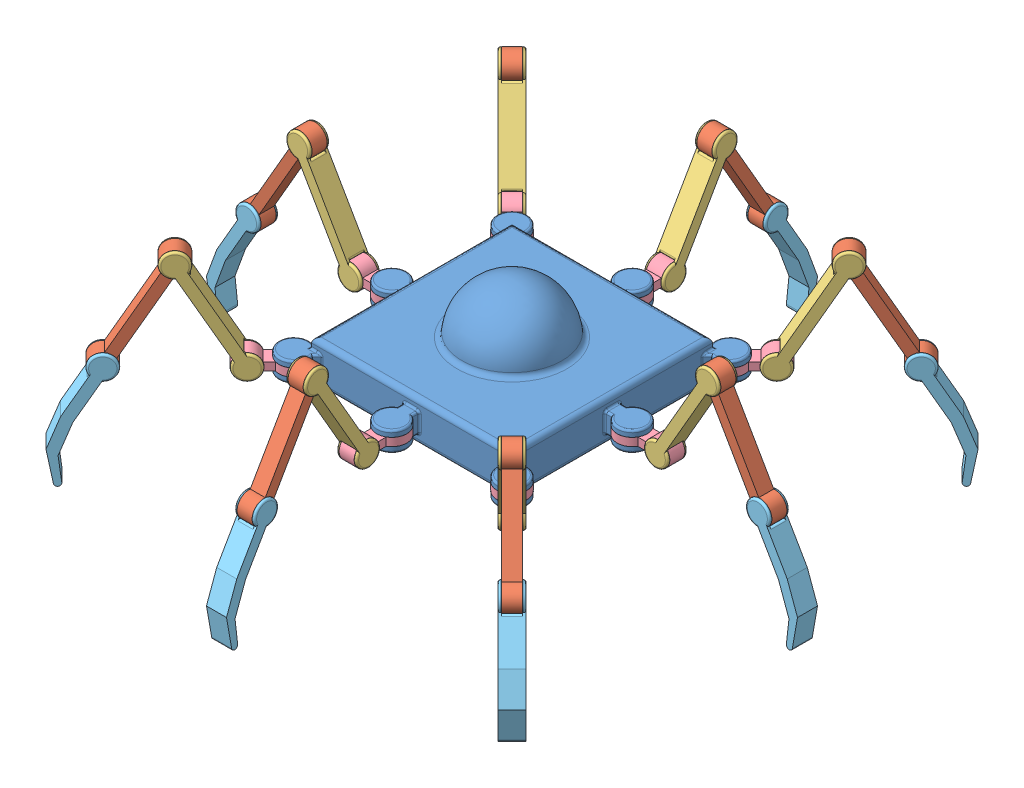
SolidWorks assembly SpiderBot_8Legs, configuration Default. Lengths in mm.
Overall size (634.89 207.45 634.89).
33 component instances, 5 part files, 146 mates.
Components (placement in the parent):
- spider_body-1: spider_body [Default] at (0 150 0) x (0 0 -1) z (0 -1 0) size (270 270 90)
- Link_C-24: Link_C [Default] at (-183.9152 176.5882 -194.5218) x (0.353553 0.866025 0.353553) z (-0.707107 0 0.707107) size (125.82 24 15)
- Link_B-24: Link_B [Default] at (-140.0258 176.5882 -154.1679) x (-0.707107 0 0.707107) z (-0.353553 0.866025 -0.353553) size (20.32 24 125.82)
- Link_A-24: Link_A [Default] at (-108.832 134 -108.832) x (-0.707107 0 -0.707107) z (0 -1 0) size (59.99 30 24)
- Link_D-24: Link_D [Default] at (-232.2874 88.4118 -218.1453) x (0.707107 0 -0.707107) z (0.353553 0.866025 0.353553) size (20.32 36.78 116.49)
- Link_C-26: Link_C [Default] at (-194.5218 176.5882 183.9152) x (0.353553 0.866025 -0.353553) z (0.707107 0 0.707107) size (125.82 24 15)
- Link_B-26: Link_B [Default] at (-154.1679 176.5882 140.0258) x (0.707107 0 0.707107) z (-0.353553 0.866025 0.353553) size (20.32 24 125.82)
- Link_A-26: Link_A [Default] at (-108.832 134 108.832) x (-0.707107 0 0.707107) z (0 -1 0) size (59.99 30 24)
- Link_D-26: Link_D [Default] at (-218.1453 88.4118 232.2874) x (-0.707107 0 -0.707107) z (0.353553 0.866025 -0.353553) size (20.32 36.78 116.49)
- Link_C-27: Link_C [Default] at (183.9152 176.5882 194.5218) x (-0.353553 0.866025 -0.353553) z (0.707107 0 -0.707107) size (125.82 24 15)
- Link_B-27: Link_B [Default] at (140.0258 176.5882 154.1679) x (0.707107 0 -0.707107) z (0.353553 0.866025 0.353553) size (20.32 24 125.82)
- Link_A-27: Link_A [Default] at (108.832 134 108.832) x (0.707107 0 0.707107) z (0 -1 0) size (59.99 30 24)
- Link_D-27: Link_D [Default] at (232.2874 88.4118 218.1453) x (-0.707107 0 0.707107) z (-0.353553 0.866025 -0.353553) size (20.32 36.78 116.49)
- Link_B-33: Link_B [Default] at (154.1679 176.5882 -140.0258) x (-0.707107 0 -0.707107) z (0.353553 0.866025 -0.353553) size (20.32 24 125.82)
- Link_D-31: Link_D [Default] at (218.1453 88.4118 -232.2874) x (0.707107 0 0.707107) z (-0.353553 0.866025 0.353553) size (20.32 36.78 116.49)
- Link_A-31: Link_A [Default] at (108.832 134 -108.832) x (0.707107 0 -0.707107) z (0 -1 0) size (59.99 30 24)
- Link_C-31: Link_C [Default] at (194.5218 176.5882 -183.9152) x (-0.353553 0.866025 0.353553) z (-0.707107 0 -0.707107) size (125.82 24 15)
- Link_D-34: Link_D [Default] at (-284.5923 88.4118 10) x (0 0 -1) z (0.5 0.866025 0) size (20.32 36.78 116.49)
- Link_A-34: Link_A [Default] at (-120 134 0) x (-1 0 0) z (0 -1 0) size (59.99 30 24)
- Link_B-36: Link_B [Default] at (-174.1146 176.5882 -10) x (0 0 1) z (-0.5 0.866025 0) size (20.32 24 125.82)
- Link_C-34: Link_C [Default] at (-233.6836 176.5882 -7.5) x (0.5 0.866025 0) z (0 0 1) size (125.82 24 15)
- Link_A-35: Link_A [Default] at (120 134 0) x (1 0 0) z (0 -1 0) size (59.99 30 24)
- Link_D-35: Link_D [Default] at (284.5923 88.4118 -10) x (0 0 1) z (-0.5 0.866025 0) size (20.32 36.78 116.49)
- Link_C-35: Link_C [Default] at (233.6836 176.5882 7.5) x (-0.5 0.866025 0) z (0 0 -1) size (125.82 24 15)
- Link_B-37: Link_B [Default] at (174.1146 176.5882 10) x (0 0 -1) z (0.5 0.866025 0) size (20.32 24 125.82)
- Link_A-36: Link_A [Default] at (0 134 120) x (0 0 1) z (0 -1 0) size (59.99 30 24)
- Link_D-36: Link_D [Default] at (10 88.4118 284.5923) x (-1 0 0) z (0 0.866025 -0.5) size (20.32 36.78 116.49)
- Link_C-36: Link_C [Default] at (-7.5 176.5882 233.6836) x (0 0.866025 -0.5) z (1 0 0) size (125.82 24 15)
- Link_B-38: Link_B [Default] at (-10 176.5882 174.1146) x (1 0 0) z (0 0.866025 0.5) size (20.32 24 125.82)
- Link_A-37: Link_A [Default] at (0 134 -120) x (0 0 -1) z (0 -1 0) size (59.99 30 24)
- Link_D-37: Link_D [Default] at (-10 88.4118 -284.5923) x (1 0 0) z (0 0.866025 0.5) size (20.32 36.78 116.49)
- Link_C-37: Link_C [Default] at (7.5 176.5882 -233.6836) x (0 0.866025 0.5) z (-1 0 0) size (125.82 24 15)
- Link_B-39: Link_B [Default] at (10 176.5882 -174.1146) x (-1 0 0) z (0 0.866025 -0.5) size (20.32 24 125.82)
Mates (geometry in assembly coordinates):
- Coincident4: coincident anti-aligned: plane of Link_B-2 through (235.0341 -365.5738 720.8033) normal (-1 0 0); plane of Link_C-2 through (235.0341 -453.7502 771.712) normal (1 0 0)
- Concentric4: concentric anti-aligned: cylinder of Link_B-2 through (220.0341 -365.5738 720.8033) axis (1 0 0) radius 4; cylinder of Link_C-2 through (235.0341 -365.5738 720.8033) axis (-1 0 0) radius 4
- Coincident5: coincident anti-aligned: plane of Link_C-2 through (235.0341 -453.7502 771.712) normal (1 0 0); plane of Link_D-2 through (235.0341 -453.7502 771.712) normal (-1 0 0)
- Concentric6: concentric aligned: cylinder of Link_C-2 through (235.0341 -453.7502 771.712) axis (-1 0 0) radius 4; cylinder of Link_D-2 through (235.0341 -453.7502 771.712) axis (-1 0 0) radius 4
- Coincident7: coincident anti-aligned: plane of Link_B-3 through (281.248 -759.0313 934.2797) normal (-1 0 0); plane of Link_C-3 through (281.248 -847.2078 985.1885) normal (1 0 0)
- Concentric7: concentric anti-aligned: cylinder of Link_B-3 through (266.248 -759.0313 934.2797) axis (1 0 0) radius 4; cylinder of Link_C-3 through (281.248 -759.0313 934.2797) axis (-1 0 0) radius 4
- Coincident8: coincident anti-aligned: plane of Link_C-3 through (281.248 -847.2078 985.1885) normal (1 0 0); plane of Link_D-3 through (281.248 -847.2078 985.1885) normal (-1 0 0)
- Concentric9: concentric aligned: cylinder of Link_C-3 through (281.248 -847.2078 985.1885) axis (-1 0 0) radius 4; cylinder of Link_D-3 through (281.248 -847.2078 985.1885) axis (-1 0 0) radius 4
- Coincident10: coincident anti-aligned: plane of Link_B-4 through (178.5336 -465.5708 822.703) normal (-1 0 0); plane of Link_C-4 through (178.5336 -553.7473 873.6117) normal (1 0 0)
- Concentric10: concentric anti-aligned: cylinder of Link_B-4 through (163.5336 -465.5708 822.703) axis (1 0 0) radius 4; cylinder of Link_C-4 through (178.5336 -465.5708 822.703) axis (-1 0 0) radius 4
- Coincident11: coincident anti-aligned: plane of Link_C-4 through (178.5336 -553.7473 873.6117) normal (1 0 0); plane of Link_D-4 through (178.5336 -553.7473 873.6117) normal (-1 0 0)
- Concentric12: concentric aligned: cylinder of Link_C-4 through (178.5336 -553.7473 873.6117) axis (-1 0 0) radius 4; cylinder of Link_D-4 through (178.5336 -553.7473 873.6117) axis (-1 0 0) radius 4
- Coincident13: coincident anti-aligned: plane of Link_B-5 through (262.376 -1013.0932 1106.1332) normal (-1 0 0); plane of Link_C-5 through (262.376 -1101.2696 1157.0419) normal (1 0 0)
- Concentric13: concentric anti-aligned: cylinder of Link_B-5 through (247.376 -1013.0932 1106.1332) axis (1 0 0) radius 4; cylinder of Link_C-5 through (262.376 -1013.0932 1106.1332) axis (-1 0 0) radius 4
- Coincident14: coincident anti-aligned: plane of Link_C-5 through (262.376 -1101.2696 1157.0419) normal (1 0 0); plane of Link_D-5 through (262.376 -1101.2696 1157.0419) normal (-1 0 0)
- Concentric15: concentric aligned: cylinder of Link_C-5 through (262.376 -1101.2696 1157.0419) axis (-1 0 0) radius 4; cylinder of Link_D-5 through (262.376 -1101.2696 1157.0419) axis (-1 0 0) radius 4
- Coincident16: coincident anti-aligned: plane of Link_B-6 through (534.9738 -1642.7072 1309.0583) normal (-1 0 0); plane of Link_C-6 through (534.9738 -1730.8837 1359.9671) normal (1 0 0)
- Concentric16: concentric anti-aligned: cylinder of Link_B-6 through (519.9738 -1642.7072 1309.0583) axis (1 0 0) radius 4; cylinder of Link_C-6 through (534.9738 -1642.7072 1309.0583) axis (-1 0 0) radius 4
- Coincident17: coincident anti-aligned: plane of Link_C-6 through (534.9738 -1730.8837 1359.9671) normal (1 0 0); plane of Link_D-6 through (534.9738 -1730.8837 1359.9671) normal (-1 0 0)
- Concentric18: concentric aligned: cylinder of Link_C-6 through (534.9738 -1730.8837 1359.9671) axis (-1 0 0) radius 4; cylinder of Link_D-6 through (534.9738 -1730.8837 1359.9671) axis (-1 0 0) radius 4
- Coincident19: coincident anti-aligned: plane of Link_B-7 through (-306.3909 -269.9837 1039.0888) normal (-1 0 0); plane of Link_C-7 through (-306.3909 -358.1602 1089.9975) normal (1 0 0)
- Concentric19: concentric anti-aligned: cylinder of Link_B-7 through (-321.3909 -269.9837 1039.0888) axis (1 0 0) radius 4; cylinder of Link_C-7 through (-306.3909 -269.9837 1039.0888) axis (-1 0 0) radius 4
- Coincident20: coincident anti-aligned: plane of Link_C-7 through (-306.3909 -358.1602 1089.9975) normal (1 0 0); plane of Link_D-7 through (-306.3909 -358.1602 1089.9975) normal (-1 0 0)
- Concentric21: concentric aligned: cylinder of Link_C-7 through (-306.3909 -358.1602 1089.9975) axis (-1 0 0) radius 4; cylinder of Link_D-7 through (-306.3909 -358.1602 1089.9975) axis (-1 0 0) radius 4
- Coincident22: coincident anti-aligned: plane of Link_B-8 through (-311.8852 -488.0983 1179.1514) normal (-1 0 0); plane of Link_C-8 through (-311.8852 -576.2747 1230.0601) normal (1 0 0)
- Concentric22: concentric anti-aligned: cylinder of Link_B-8 through (-326.8852 -488.0983 1179.1514) axis (1 0 0) radius 4; cylinder of Link_C-8 through (-311.8852 -488.0983 1179.1514) axis (-1 0 0) radius 4
- Coincident23: coincident anti-aligned: plane of Link_C-8 through (-311.8852 -576.2747 1230.0601) normal (1 0 0); plane of Link_D-8 through (-311.8852 -576.2747 1230.0601) normal (-1 0 0)
- Concentric24: concentric aligned: cylinder of Link_C-8 through (-311.8852 -576.2747 1230.0601) axis (-1 0 0) radius 4; cylinder of Link_D-8 through (-311.8852 -576.2747 1230.0601) axis (-1 0 0) radius 4
- Coincident25: coincident anti-aligned: plane of Link_B-9 through (-611.4857 -390.9688 1327.6493) normal (-1 0 0); plane of Link_C-9 through (-611.4857 -479.1453 1378.558) normal (1 0 0)
- Concentric25: concentric anti-aligned: cylinder of Link_B-9 through (-626.4857 -390.9688 1327.6493) axis (1 0 0) radius 4; cylinder of Link_C-9 through (-611.4857 -390.9688 1327.6493) axis (-1 0 0) radius 4
- Coincident26: coincident anti-aligned: plane of Link_C-9 through (-611.4857 -479.1453 1378.558) normal (1 0 0); plane of Link_D-9 through (-611.4857 -479.1453 1378.558) normal (-1 0 0)
- Concentric27: concentric aligned: cylinder of Link_C-9 through (-611.4857 -479.1453 1378.558) axis (-1 0 0) radius 4; cylinder of Link_D-9 through (-611.4857 -479.1453 1378.558) axis (-1 0 0) radius 4
- Coincident28: coincident anti-aligned: plane of Link_B-10 through (-139.42 -657.5126 1164.5577) normal (-1 0 0); plane of Link_C-10 through (-139.42 -745.689 1215.4664) normal (1 0 0)
- Concentric28: concentric anti-aligned: cylinder of Link_B-10 through (-154.42 -657.5126 1164.5577) axis (1 0 0) radius 4; cylinder of Link_C-10 through (-139.42 -657.5126 1164.5577) axis (-1 0 0) radius 4
- Coincident29: coincident anti-aligned: plane of Link_C-10 through (-139.42 -745.689 1215.4664) normal (1 0 0); plane of Link_D-10 through (-139.42 -745.689 1215.4664) normal (-1 0 0)
- Concentric30: concentric aligned: cylinder of Link_C-10 through (-139.42 -745.689 1215.4664) axis (-1 0 0) radius 4; cylinder of Link_D-10 through (-139.42 -745.689 1215.4664) axis (-1 0 0) radius 4
- Coincident31: coincident anti-aligned: plane of Link_B-11 through (-139.42 -657.5126 1164.5577) normal (-1 0 0); plane of Link_C-11 through (-139.42 -745.689 1215.4664) normal (1 0 0)
- Concentric31: concentric anti-aligned: cylinder of Link_B-11 through (-154.42 -657.5126 1164.5577) axis (1 0 0) radius 4; cylinder of Link_C-11 through (-139.42 -657.5126 1164.5577) axis (-1 0 0) radius 4
- Coincident32: coincident anti-aligned: plane of Link_C-11 through (-139.42 -745.689 1215.4664) normal (1 0 0); plane of Link_D-11 through (-139.42 -745.689 1215.4664) normal (-1 0 0)
- Concentric33: concentric aligned: cylinder of Link_C-11 through (-139.42 -745.689 1215.4664) axis (-1 0 0) radius 4; cylinder of Link_D-11 through (-139.42 -745.689 1215.4664) axis (-1 0 0) radius 4
- Coincident34: coincident anti-aligned: plane of Link_B-12 through (-94.7509 -804.43 1225.1322) normal (-1 0 0); plane of Link_C-12 through (-94.7509 -892.6065 1276.0409) normal (1 0 0)
- Concentric34: concentric anti-aligned: cylinder of Link_B-12 through (-109.7509 -804.43 1225.1322) axis (1 0 0) radius 4; cylinder of Link_C-12 through (-94.7509 -804.43 1225.1322) axis (-1 0 0) radius 4
- Coincident35: coincident anti-aligned: plane of Link_C-12 through (-94.7509 -892.6065 1276.0409) normal (1 0 0); plane of Link_D-12 through (-94.7509 -892.6065 1276.0409) normal (-1 0 0)
- Concentric36: concentric aligned: cylinder of Link_C-12 through (-94.7509 -892.6065 1276.0409) axis (-1 0 0) radius 4; cylinder of Link_D-12 through (-94.7509 -892.6065 1276.0409) axis (-1 0 0) radius 4
- Concentric78: concentric anti-aligned: cylinder of Link_C-24 through (-173.461 218.1765 -162.8544) axis (0.707107 0 -0.707107) radius 4; cylinder of Link_B-24 through (-162.8544 218.1765 -173.461) axis (-0.707107 0 0.707107) radius 4
- Concentric79: concentric anti-aligned: cylinder of Link_B-24 through (-126.8565 130 -137.4631) axis (-0.707107 0 0.707107) radius 4; cylinder of Link_A-24 through (-142.7664 130 -121.5532) axis (0.707107 0 -0.707107) radius 5
- Coincident86: coincident anti-aligned: plane of Link_B-24 through (-137.4631 130 -126.8565) normal (0.707107 0 -0.707107); plane of Link_A-24 through (-123.3209 126 -112.7143) normal (-0.707107 0 0.707107)
- Coincident87: coincident anti-aligned: plane of Link_C-24 through (-198.8522 130 -209.4588) normal (0.707107 0 -0.707107); plane of Link_B-24 through (-162.8544 218.1765 -173.461) normal (-0.707107 0 0.707107)
- Coincident88: coincident anti-aligned: plane of Link_C-24 through (-209.4588 130 -198.8522) normal (-0.707107 0 0.707107); plane of Link_B-24 through (-173.461 218.1765 -162.8544) normal (0.707107 0 -0.707107)
- Coincident89: coincident anti-aligned: plane of Link_C-24 through (-198.8522 130 -209.4588) normal (0.707107 0 -0.707107); plane of Link_D-24 through (-198.8522 130 -209.4588) normal (-0.707107 0 0.707107)
- Concentric80: concentric aligned: cylinder of Link_C-24 through (-209.4588 130 -198.8522) axis (0.707107 0 -0.707107) radius 4; cylinder of Link_D-24 through (-209.4588 130 -198.8522) axis (0.707107 0 -0.707107) radius 4
- Coincident90: coincident anti-aligned: plane of Link_B-24 through (-126.8565 130 -137.4631) normal (-0.707107 0 0.707107); plane of Link_A-24 through (-112.7143 126 -123.3209) normal (0.707107 0 -0.707107)
- Coincident91: coincident anti-aligned: plane of Link_C-24 through (-209.4588 130 -198.8522) normal (-0.707107 0 0.707107); plane of Link_D-24 through (-209.4588 130 -198.8522) normal (0.707107 0 -0.707107)
- Concentric84: concentric anti-aligned: cylinder of Link_C-26 through (-162.8544 218.1765 173.461) axis (-0.707107 0 -0.707107) radius 4; cylinder of Link_B-26 through (-173.461 218.1765 162.8544) axis (0.707107 0 0.707107) radius 4
- Concentric85: concentric anti-aligned: cylinder of Link_B-26 through (-137.4631 130 126.8565) axis (0.707107 0 0.707107) radius 4; cylinder of Link_A-26 through (-121.5532 130 142.7664) axis (-0.707107 0 -0.707107) radius 5
- Coincident98: coincident anti-aligned: plane of Link_B-26 through (-126.8565 130 137.4631) normal (-0.707107 0 -0.707107); plane of Link_A-26 through (-112.7143 126 123.3209) normal (0.707107 0 0.707107)
- Coincident99: coincident anti-aligned: plane of Link_C-26 through (-209.4588 130 198.8522) normal (-0.707107 0 -0.707107); plane of Link_B-26 through (-173.461 218.1765 162.8544) normal (0.707107 0 0.707107)
- Coincident100: coincident anti-aligned: plane of Link_C-26 through (-198.8522 130 209.4588) normal (0.707107 0 0.707107); plane of Link_B-26 through (-162.8544 218.1765 173.461) normal (-0.707107 0 -0.707107)
- Coincident101: coincident anti-aligned: plane of Link_C-26 through (-209.4588 130 198.8522) normal (-0.707107 0 -0.707107); plane of Link_D-26 through (-209.4588 130 198.8522) normal (0.707107 0 0.707107)
- Concentric86: concentric aligned: cylinder of Link_C-26 through (-198.8522 130 209.4588) axis (-0.707107 0 -0.707107) radius 4; cylinder of Link_D-26 through (-198.8522 130 209.4588) axis (-0.707107 0 -0.707107) radius 4
- Coincident102: coincident anti-aligned: plane of Link_B-26 through (-137.4631 130 126.8565) normal (0.707107 0 0.707107); plane of Link_A-26 through (-123.3209 126 112.7143) normal (-0.707107 0 -0.707107)
- Coincident103: coincident anti-aligned: plane of Link_C-26 through (-198.8522 130 209.4588) normal (0.707107 0 0.707107); plane of Link_D-26 through (-198.8522 130 209.4588) normal (-0.707107 0 -0.707107)
- Concentric87: concentric anti-aligned: cylinder of Link_C-27 through (173.461 218.1765 162.8544) axis (-0.707107 0 0.707107) radius 4; cylinder of Link_B-27 through (162.8544 218.1765 173.461) axis (0.707107 0 -0.707107) radius 4
- Concentric88: concentric anti-aligned: cylinder of Link_B-27 through (126.8565 130 137.4631) axis (0.707107 0 -0.707107) radius 4; cylinder of Link_A-27 through (142.7664 130 121.5532) axis (-0.707107 0 0.707107) radius 5
- Coincident104: coincident anti-aligned: plane of Link_B-27 through (137.4631 130 126.8565) normal (-0.707107 0 0.707107); plane of Link_A-27 through (123.3209 126 112.7143) normal (0.707107 0 -0.707107)
- Coincident105: coincident anti-aligned: plane of Link_C-27 through (198.8522 130 209.4588) normal (-0.707107 0 0.707107); plane of Link_B-27 through (162.8544 218.1765 173.461) normal (0.707107 0 -0.707107)
- Coincident106: coincident anti-aligned: plane of Link_C-27 through (209.4588 130 198.8522) normal (0.707107 0 -0.707107); plane of Link_B-27 through (173.461 218.1765 162.8544) normal (-0.707107 0 0.707107)
- Coincident107: coincident anti-aligned: plane of Link_C-27 through (198.8522 130 209.4588) normal (-0.707107 0 0.707107); plane of Link_D-27 through (198.8522 130 209.4588) normal (0.707107 0 -0.707107)
- Concentric89: concentric aligned: cylinder of Link_C-27 through (209.4588 130 198.8522) axis (-0.707107 0 0.707107) radius 4; cylinder of Link_D-27 through (209.4588 130 198.8522) axis (-0.707107 0 0.707107) radius 4
- Coincident108: coincident anti-aligned: plane of Link_B-27 through (126.8565 130 137.4631) normal (0.707107 0 -0.707107); plane of Link_A-27 through (112.7143 126 123.3209) normal (-0.707107 0 0.707107)
- Coincident109: coincident anti-aligned: plane of Link_C-27 through (209.4588 130 198.8522) normal (0.707107 0 -0.707107); plane of Link_D-27 through (209.4588 130 198.8522) normal (-0.707107 0 0.707107)
- Coincident124: coincident anti-aligned: plane of spider_body-1 through (108.832 134 108.832) normal (0 -1 0); plane of Link_A-27 through (108.832 134 108.832) normal (0 1 0)
- Coincident125: coincident anti-aligned: plane of spider_body-1 through (108.832 126 108.832) normal (0 1 0); plane of Link_A-27 through (108.832 126 108.832) normal (0 -1 0)
- Concentric97: concentric anti-aligned: cylinder of spider_body-1 through (108.832 134 108.832) axis (0 -1 0) radius 10; cylinder of Link_A-27 through (108.832 126 108.832) axis (0 1 0) radius 10
- Coincident126: coincident anti-aligned: plane of spider_body-1 through (-108.832 134 108.832) normal (0 -1 0); plane of Link_A-26 through (-108.832 134 108.832) normal (0 1 0)
- Coincident127: coincident anti-aligned: plane of spider_body-1 through (-108.832 126 108.832) normal (0 1 0); plane of Link_A-26 through (-108.832 126 108.832) normal (0 -1 0)
- Concentric98: concentric anti-aligned: cylinder of spider_body-1 through (-108.832 134 108.832) axis (0 -1 0) radius 10; cylinder of Link_A-26 through (-108.832 126 108.832) axis (0 1 0) radius 10
- Coincident138: coincident anti-aligned: plane of Link_B-33 through (162.8544 218.1765 -173.461) normal (0.707107 0 0.707107); plane of Link_C-31 through (198.8522 130 -209.4588) normal (-0.707107 0 -0.707107)
- Coincident139: coincident anti-aligned: plane of Link_D-31 through (209.4588 130 -198.8522) normal (-0.707107 0 -0.707107); plane of Link_C-31 through (209.4588 130 -198.8522) normal (0.707107 0 0.707107)
- Coincident140: coincident anti-aligned: plane of Link_D-31 through (198.8522 130 -209.4588) normal (0.707107 0 0.707107); plane of Link_C-31 through (198.8522 130 -209.4588) normal (-0.707107 0 -0.707107)
- Concentric104: concentric aligned: cylinder of Link_D-31 through (198.8522 130 -209.4588) axis (0.707107 0 0.707107) radius 4; cylinder of Link_C-31 through (198.8522 130 -209.4588) axis (0.707107 0 0.707107) radius 4
- Coincident141: coincident anti-aligned: plane of Link_B-33 through (137.4631 130 -126.8565) normal (-0.707107 0 -0.707107); plane of Link_A-31 through (123.3209 126 -112.7143) normal (0.707107 0 0.707107)
- Concentric105: concentric anti-aligned: cylinder of Link_B-33 through (173.461 218.1765 -162.8544) axis (-0.707107 0 -0.707107) radius 4; cylinder of Link_C-31 through (162.8544 218.1765 -173.461) axis (0.707107 0 0.707107) radius 4
- Concentric106: concentric anti-aligned: cylinder of Link_B-33 through (137.4631 130 -126.8565) axis (-0.707107 0 -0.707107) radius 4; cylinder of Link_A-31 through (121.5532 130 -142.7664) axis (0.707107 0 0.707107) radius 5
- Coincident142: coincident anti-aligned: plane of Link_B-33 through (126.8565 130 -137.4631) normal (0.707107 0 0.707107); plane of Link_A-31 through (112.7143 126 -123.3209) normal (-0.707107 0 -0.707107)
- Coincident143: coincident anti-aligned: plane of Link_B-33 through (173.461 218.1765 -162.8544) normal (-0.707107 0 -0.707107); plane of Link_C-31 through (209.4588 130 -198.8522) normal (0.707107 0 0.707107)
- Coincident146: coincident anti-aligned: plane of spider_body-1 through (108.832 134 -108.832) normal (0 -1 0); plane of Link_A-31 through (108.832 134 -108.832) normal (0 1 0)
- Coincident147: coincident anti-aligned: plane of spider_body-1 through (108.832 126 -108.832) normal (0 1 0); plane of Link_A-31 through (108.832 126 -108.832) normal (0 -1 0)
- Concentric108: concentric anti-aligned: cylinder of spider_body-1 through (108.832 134 -108.832) axis (0 -1 0) radius 10; cylinder of Link_A-31 through (108.832 126 -108.832) axis (0 1 0) radius 10
- Coincident148: coincident anti-aligned: plane of spider_body-1 through (-108.832 134 -108.832) normal (0 -1 0); plane of Link_A-24 through (-108.832 134 -108.832) normal (0 1 0)
- Coincident149: coincident anti-aligned: plane of spider_body-1 through (-108.832 126 -108.832) normal (0 1 0); plane of Link_A-24 through (-108.832 126 -108.832) normal (0 -1 0)
- Concentric109: concentric anti-aligned: cylinder of spider_body-1 through (-108.832 134 -108.832) axis (0 -1 0) radius 10; cylinder of Link_A-24 through (-108.832 126 -108.832) axis (0 1 0) radius 10
- Concentric111: concentric anti-aligned: cylinder of Link_A-32 through (-1752.5654 2022.5976 -1745.769) axis (0.707107 0 -0.707107) radius 5; cylinder of Link_B-34 through (-1736.6555 2022.5976 -1761.6789) axis (-0.707107 0 0.707107) radius 4
- Coincident151: coincident anti-aligned: plane of Link_B-34 through (-1783.26 2110.774 -1787.0702) normal (0.707107 0 -0.707107); plane of Link_C-32 through (-1819.2579 2022.5976 -1823.0681) normal (-0.707107 0 0.707107)
- Concentric112: concentric anti-aligned: cylinder of Link_B-34 through (-1772.6534 2110.774 -1797.6768) axis (-0.707107 0 0.707107) radius 4; cylinder of Link_C-32 through (-1783.26 2110.774 -1787.0702) axis (0.707107 0 -0.707107) radius 4
- Coincident153: coincident anti-aligned: plane of Link_A-32 through (-1733.12 2018.5976 -1736.9302) normal (-0.707107 0 0.707107); plane of Link_B-34 through (-1747.2621 2022.5976 -1751.0723) normal (0.707107 0 -0.707107)
- Coincident154: coincident anti-aligned: plane of Link_B-34 through (-1772.6534 2110.774 -1797.6768) normal (-0.707107 0 0.707107); plane of Link_C-32 through (-1808.6513 2022.5976 -1833.6747) normal (0.707107 0 -0.707107)
- Coincident155: coincident anti-aligned: plane of Link_A-32 through (-1722.5134 2018.5976 -1747.5368) normal (0.707107 0 -0.707107); plane of Link_B-34 through (-1736.6555 2022.5976 -1761.6789) normal (-0.707107 0 0.707107)
- Concentric116: concentric aligned: cylinder of Link_D-34 through (-254.8078 130 7.5) axis (0 0 -1) radius 4; cylinder of Link_C-34 through (-254.8078 130 7.5) axis (0 0 -1) radius 4
- Coincident162: coincident anti-aligned: plane of Link_D-34 through (-254.8078 130 7.5) normal (0 0 -1); plane of Link_C-34 through (-254.8078 130 7.5) normal (0 0 1)
- Concentric117: concentric anti-aligned: cylinder of Link_A-34 through (-152.9904 130 15) axis (0 0 -1) radius 5; cylinder of Link_B-36 through (-152.9904 130 -7.5) axis (0 0 1) radius 4
- Coincident163: coincident anti-aligned: plane of Link_B-36 through (-203.8991 218.1765 7.5) normal (0 0 -1); plane of Link_C-34 through (-254.8078 130 7.5) normal (0 0 1)
- Concentric118: concentric anti-aligned: cylinder of Link_B-36 through (-203.8991 218.1765 -7.5) axis (0 0 1) radius 4; cylinder of Link_C-34 through (-203.8991 218.1765 7.5) axis (0 0 -1) radius 4
- Coincident164: coincident anti-aligned: plane of Link_D-34 through (-254.8078 130 -7.5) normal (0 0 1); plane of Link_C-34 through (-254.8078 130 -7.5) normal (0 0 -1)
- Coincident165: coincident anti-aligned: plane of Link_A-34 through (-132.9904 126 7.5) normal (0 0 1); plane of Link_B-36 through (-152.9904 130 7.5) normal (0 0 -1)
- Coincident166: coincident anti-aligned: plane of Link_B-36 through (-203.8991 218.1765 -7.5) normal (0 0 1); plane of Link_C-34 through (-254.8078 130 -7.5) normal (0 0 -1)
- Coincident167: coincident anti-aligned: plane of Link_A-34 through (-132.9904 126 -7.5) normal (0 0 -1); plane of Link_B-36 through (-152.9904 130 -7.5) normal (0 0 1)
- Concentric119: concentric aligned: cylinder of Link_D-35 through (254.8078 130 -7.5) axis (0 0 1) radius 4; cylinder of Link_C-35 through (254.8078 130 -7.5) axis (0 0 1) radius 4
- Concentric120: concentric anti-aligned: cylinder of Link_C-35 through (203.8991 218.1765 -7.5) axis (0 0 1) radius 4; cylinder of Link_B-37 through (203.8991 218.1765 7.5) axis (0 0 -1) radius 4
- Coincident168: coincident anti-aligned: plane of Link_A-35 through (132.9904 126 7.5) normal (0 0 1); plane of Link_B-37 through (152.9904 130 7.5) normal (0 0 -1)
- Coincident169: coincident anti-aligned: plane of Link_A-35 through (132.9904 126 -7.5) normal (0 0 -1); plane of Link_B-37 through (152.9904 130 -7.5) normal (0 0 1)
- Coincident170: coincident anti-aligned: plane of Link_D-35 through (254.8078 130 -7.5) normal (0 0 1); plane of Link_C-35 through (254.8078 130 -7.5) normal (0 0 -1)
- Concentric121: concentric anti-aligned: cylinder of Link_A-35 through (152.9904 130 -15) axis (0 0 1) radius 5; cylinder of Link_B-37 through (152.9904 130 7.5) axis (0 0 -1) radius 4
- Coincident171: coincident anti-aligned: plane of Link_C-35 through (254.8078 130 -7.5) normal (0 0 -1); plane of Link_B-37 through (203.8991 218.1765 -7.5) normal (0 0 1)
- Coincident172: coincident anti-aligned: plane of Link_D-35 through (254.8078 130 7.5) normal (0 0 -1); plane of Link_C-35 through (254.8078 130 7.5) normal (0 0 1)
- Coincident173: coincident anti-aligned: plane of Link_C-35 through (254.8078 130 7.5) normal (0 0 1); plane of Link_B-37 through (203.8991 218.1765 7.5) normal (0 0 -1)
- Concentric122: concentric aligned: cylinder of Link_D-36 through (7.5 130 254.8078) axis (-1 0 0) radius 4; cylinder of Link_C-36 through (7.5 130 254.8078) axis (-1 0 0) radius 4
- Concentric123: concentric anti-aligned: cylinder of Link_C-36 through (7.5 218.1765 203.8991) axis (-1 0 0) radius 4; cylinder of Link_B-38 through (-7.5 218.1765 203.8991) axis (1 0 0) radius 4
- Coincident174: coincident anti-aligned: plane of Link_A-36 through (-7.5 126 132.9904) normal (-1 0 0); plane of Link_B-38 through (-7.5 130 152.9904) normal (1 0 0)
- Coincident175: coincident anti-aligned: plane of Link_A-36 through (7.5 126 132.9904) normal (1 0 0); plane of Link_B-38 through (7.5 130 152.9904) normal (-1 0 0)
- Coincident176: coincident anti-aligned: plane of Link_D-36 through (7.5 130 254.8078) normal (-1 0 0); plane of Link_C-36 through (7.5 130 254.8078) normal (1 0 0)
- Concentric124: concentric anti-aligned: cylinder of Link_A-36 through (15 130 152.9904) axis (-1 0 0) radius 5; cylinder of Link_B-38 through (-7.5 130 152.9904) axis (1 0 0) radius 4
- Coincident177: coincident anti-aligned: plane of Link_C-36 through (7.5 130 254.8078) normal (1 0 0); plane of Link_B-38 through (7.5 218.1765 203.8991) normal (-1 0 0)
- Coincident178: coincident anti-aligned: plane of Link_D-36 through (-7.5 130 254.8078) normal (1 0 0); plane of Link_C-36 through (-7.5 130 254.8078) normal (-1 0 0)
- Coincident179: coincident anti-aligned: plane of Link_C-36 through (-7.5 130 254.8078) normal (-1 0 0); plane of Link_B-38 through (-7.5 218.1765 203.8991) normal (1 0 0)
- Concentric125: concentric aligned: cylinder of Link_D-37 through (-7.5 130 -254.8078) axis (1 0 0) radius 4; cylinder of Link_C-37 through (-7.5 130 -254.8078) axis (1 0 0) radius 4
- Concentric126: concentric anti-aligned: cylinder of Link_C-37 through (-7.5 218.1765 -203.8991) axis (1 0 0) radius 4; cylinder of Link_B-39 through (7.5 218.1765 -203.8991) axis (-1 0 0) radius 4
- Coincident180: coincident anti-aligned: plane of Link_A-37 through (7.5 126 -132.9904) normal (1 0 0); plane of Link_B-39 through (7.5 130 -152.9904) normal (-1 0 0)
- Coincident181: coincident anti-aligned: plane of Link_A-37 through (-7.5 126 -132.9904) normal (-1 0 0); plane of Link_B-39 through (-7.5 130 -152.9904) normal (1 0 0)
- Coincident182: coincident anti-aligned: plane of Link_D-37 through (-7.5 130 -254.8078) normal (1 0 0); plane of Link_C-37 through (-7.5 130 -254.8078) normal (-1 0 0)
- Concentric127: concentric anti-aligned: cylinder of Link_A-37 through (-15 130 -152.9904) axis (1 0 0) radius 5; cylinder of Link_B-39 through (7.5 130 -152.9904) axis (-1 0 0) radius 4
- Coincident183: coincident anti-aligned: plane of Link_C-37 through (-7.5 130 -254.8078) normal (-1 0 0); plane of Link_B-39 through (-7.5 218.1765 -203.8991) normal (1 0 0)
- Coincident184: coincident anti-aligned: plane of Link_D-37 through (7.5 130 -254.8078) normal (-1 0 0); plane of Link_C-37 through (7.5 130 -254.8078) normal (1 0 0)
- Coincident185: coincident anti-aligned: plane of Link_C-37 through (7.5 130 -254.8078) normal (1 0 0); plane of Link_B-39 through (7.5 218.1765 -203.8991) normal (-1 0 0)
- Coincident187: coincident anti-aligned: plane of spider_body-1 through (-120 134 0) normal (0 -1 0); plane of Link_A-34 through (-120 134 0) normal (0 1 0)
- Coincident188: coincident anti-aligned: plane of spider_body-1 through (-120 126 0) normal (0 1 0); plane of Link_A-34 through (-120 126 0) normal (0 -1 0)
- Concentric129: concentric anti-aligned: cylinder of spider_body-1 through (-120 134 0) axis (0 -1 0) radius 10; cylinder of Link_A-34 through (-120 126 0) axis (0 1 0) radius 10
- Coincident189: coincident anti-aligned: plane of spider_body-1 through (0 134 -120) normal (0 -1 0); plane of Link_A-37 through (0 134 -120) normal (0 1 0)
- Coincident190: coincident anti-aligned: plane of spider_body-1 through (0 126 -120) normal (0 1 0); plane of Link_A-37 through (0 126 -120) normal (0 -1 0)
- Concentric130: concentric anti-aligned: cylinder of spider_body-1 through (0 134 -120) axis (0 -1 0) radius 10; cylinder of Link_A-37 through (0 126 -120) axis (0 1 0) radius 10
- Coincident191: coincident anti-aligned: plane of spider_body-1 through (120 134 0) normal (0 -1 0); plane of Link_A-35 through (120 134 0) normal (0 1 0)
- Coincident192: coincident anti-aligned: plane of spider_body-1 through (120 126 0) normal (0 1 0); plane of Link_A-35 through (120 126 0) normal (0 -1 0)
- Concentric131: concentric anti-aligned: cylinder of spider_body-1 through (120 134 0) axis (0 -1 0) radius 10; cylinder of Link_A-35 through (120 126 0) axis (0 1 0) radius 10
- Coincident193: coincident anti-aligned: plane of spider_body-1 through (0 134 120) normal (0 -1 0); plane of Link_A-36 through (0 134 120) normal (0 1 0)
- Coincident194: coincident anti-aligned: plane of spider_body-1 through (0 126 120) normal (0 1 0); plane of Link_A-36 through (0 126 120) normal (0 -1 0)
- Concentric132: concentric anti-aligned: cylinder of spider_body-1 through (0 134 120) axis (0 -1 0) radius 10; cylinder of Link_A-36 through (0 126 120) axis (0 1 0) radius 10
